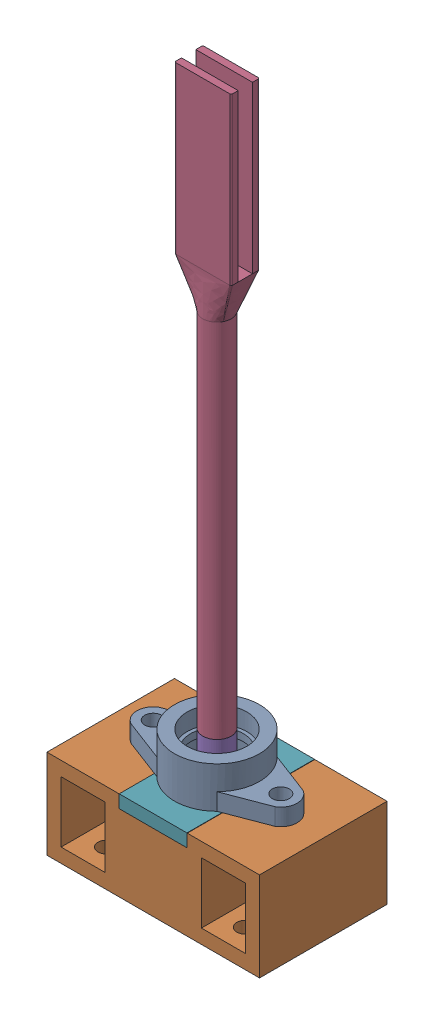
SolidWorks assembly Pole_rig, configuration Default. Lengths in mm.
Overall size (150 494.76 90).
5 component instances, 5 part files, 9 mates.
Components (placement in the parent):
- pole_rig_bearing-1: pole_rig_bearing [Default] at (-3.3158 -11.3436 -0.3268) size (113 29 60)
- pole_rig_bearing_mount-1: pole_rig_bearing_mount [Default] at (-3.3158 -74.3936 44.6732) size (150 63 90)
- pole_rig_dog_mount-1: pole_rig_dog_mount [Default] at (-3.3158 -14.9304 -0.3268) size (40.02 440.3 20.1)
- pole_rig_encoder-1: pole_rig_encoder [Default] at (-3.3158 -55.4436 -0.3268) size (30 46.55 30)
- bearing_mount_cover_plate-1: bearing_mount_cover_plate [Default] at (-27.3158 -20.4436 44.6732) size (47.8 9.1 90)
Mates (geometry in assembly coordinates):
- Concentric1: concentric anti-aligned: circle of pole_rig_bearing_mount-1; circle of pole_rig_encoder-1
- Concentric2: concentric aligned: circle of pole_rig_bearing_mount-1; circle of pole_rig_encoder-1
- Coincident2: coincident anti-aligned: plane of pole_rig_bearing_mount-1 through (-99.4892 -25.4436 -36.3268) normal (0 -1 0); plane of pole_rig_encoder-1 through (-3.3158 -25.4436 -0.3268) normal (0 1 0)
- Concentric3: concentric aligned: circle of pole_rig_bearing-1; circle of pole_rig_dog_mount-1
- Coincident3: coincident anti-aligned: plane of pole_rig_bearing_mount-1 through (-99.4892 -20.4436 -36.3268) normal (0 1 0); plane of bearing_mount_cover_plate-1 through (-27.3158 -20.4436 44.6732) normal (0 -1 0)
- Coincident4: coincident anti-aligned: plane of pole_rig_bearing_mount-1 through (-27.3158 -11.3936 -36.3268) normal (1 0 0); plane of bearing_mount_cover_plate-1 through (-27.3158 -11.3436 44.6732) normal (-1 0 0)
- Coincident5: coincident aligned: plane of pole_rig_bearing_mount-1 through (-68.3158 -64.3936 44.6732) normal (0 0 1); plane of bearing_mount_cover_plate-1 through (-27.3158 -11.3436 44.6732) normal (0 0 1)
- Coincident6: coincident anti-aligned: circle of pole_rig_bearing-1; plane of bearing_mount_cover_plate-1 through (-27.3158 -11.3436 44.6732) normal (0 1 0)
- Concentric4: concentric anti-aligned: circle of pole_rig_bearing-1; circle of pole_rig_bearing_mount-1
